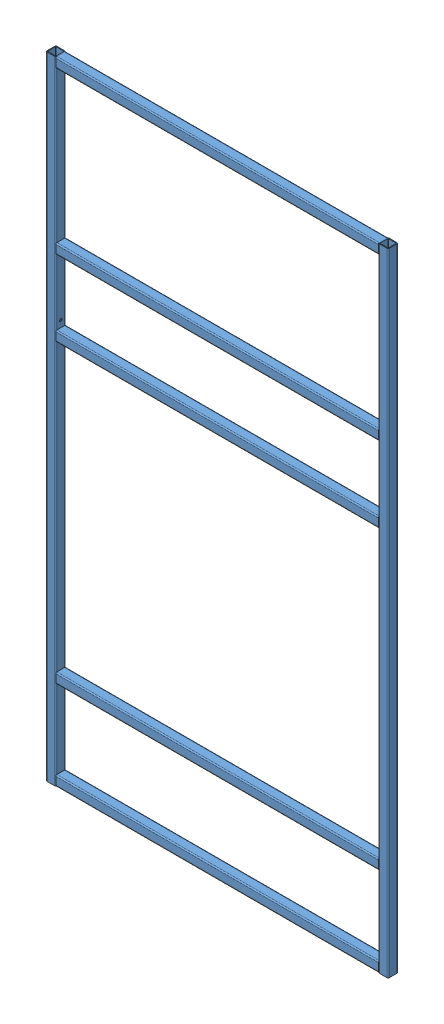
SolidWorks assembly 3D-printer R3 01.01.01 ASM side, configuration 15x15. Lengths in mm.
Overall size (520 960 15).
8 component instances, 2 part files, 21 mates.
Components (placement in the parent):
- dummy-1: dummy [По умолчанию] at origin (suppressed, hidden)
- 3D-printer R3 01.00.01 frame pipe-1: 3D-printer R3 01.00.01 frame pipe [01.00.01] at (252.5 0 7.5) x (1 0 0) z (0 1 0) size (15 15 960)
- 3D-printer R3 01.00.01 frame pipe-2: 3D-printer R3 01.00.01 frame pipe [01.00.01] at (-252.5 0 7.5) x (0 0 1) z (0 1 0) size (15 15 960)
- 3D-printer R3 01.00.01 frame pipe-3: 3D-printer R3 01.00.01 frame pipe [01.00.03] at (0 7.5 7.5) x (0 0 1) z (-1 0 0) size (15 15 490)
- 3D-printer R3 01.00.01 frame pipe-4: 3D-printer R3 01.00.01 frame pipe [01.00.03] at (0 142.5 7.5) x (0 0 -1) z (1 0 0) size (15 15 490)
- 3D-printer R3 01.00.01 frame pipe-5: 3D-printer R3 01.00.01 frame pipe [01.00.03] at (0 592.5 7.5) x (0 0 1) z (-1 0 0) size (15 15 490)
- 3D-printer R3 01.00.01 frame pipe-6: 3D-printer R3 01.00.01 frame pipe [01.00.03] at (0 707.5 7.5) x (0 0 -1) z (1 0 0) size (15 15 490)
- 3D-printer R3 01.00.01 frame pipe-7: 3D-printer R3 01.00.01 frame pipe [01.00.03] at (0 952.5 7.5) x (0 0 -1) z (1 0 0) size (15 15 490)
Mates (geometry in assembly coordinates):
- Coincident3: coincident anti-aligned: plane of 3D-printer R3 01.00.01 frame pipe-3 through (0 7.5 7.5) normal (-1 0 0); plane of assembly through (0 0 0) normal (1 0 0)
- Coincident13: coincident anti-aligned: plane of 3D-printer R3 01.00.01 frame pipe-3 through (245 7.5 7.5) normal (1 0 0); plane of 3D-printer R3 01.00.01 frame pipe-1 through (245 960 1.7) normal (-1 0 0)
- Coincident15: coincident aligned: plane of 3D-printer R3 01.00.01 frame pipe-1 through (252.5 0 7.5) normal (0 1 0); plane of 3D-printer R3 01.00.01 frame pipe-2 through (-252.5 0 7.5) normal (0 1 0)
- Coincident16: coincident anti-aligned: plane of 3D-printer R3 01.00.01 frame pipe-3 through (-245 7.5 7.5) normal (-1 0 0); plane of 3D-printer R3 01.00.01 frame pipe-2 through (-245 960 1.7) normal (1 0 0)
- Coincident17: coincident aligned: plane of 3D-printer R3 01.00.01 frame pipe-3 through (-245 13.3 15) normal (0 0 1); plane of 3D-printer R3 01.00.01 frame pipe-2 through (-245 960 1.7) normal (1 0 0)
- Coincident28: coincident aligned: plane of 3D-printer R3 01.00.01 frame pipe-4 through (245 150 13.3) normal (0 1 0); plane of assembly through (0 150 0) normal (0 1 0)
- Coincident29: coincident aligned: plane of 3D-printer R3 01.00.01 frame pipe-4 through (0 142.5 7.5) normal (1 0 0); plane of assembly through (0 0 0) normal (1 0 0)
- Coincident33: coincident aligned: plane of 3D-printer R3 01.00.01 frame pipe-6 through (245 715 13.3) normal (0 1 0); plane of assembly
- Coincident34: coincident aligned: plane of 3D-printer R3 01.00.01 frame pipe-6 through (0 707.5 7.5) normal (1 0 0); plane of assembly through (0 0 0) normal (1 0 0)
- Coincident36: coincident aligned: plane of 3D-printer R3 01.00.01 frame pipe-7 through (0 952.5 7.5) normal (1 0 0); plane of assembly through (0 0 0) normal (1 0 0)
- Coincident38: coincident aligned: plane of assembly through (0 0 0) normal (0 1 0); plane of 3D-printer R3 01.00.01 frame pipe-1 through (252.5 0 7.5) normal (0 1 0)
- Distance2: distance = 100 mm anti-aligned: plane of 3D-printer R3 01.00.01 frame pipe-6 through (245 700 13.3) normal (0 -1 0); plane of 3D-printer R3 01.00.01 frame pipe-5 through (-245 600 1.7) normal (0 1 0)
- Coincident41: coincident anti-aligned: plane of 3D-printer R3 01.00.01 frame pipe-1 through (245 960 1.7) normal (-1 0 0); plane of 3D-printer R3 01.00.01 frame pipe-5 through (245 592.5 7.5) normal (1 0 0)
- Coincident46: coincident anti-aligned: plane of 3D-printer R3 01.00.01 frame pipe-5 through (-245 585 1.7) normal (0 -1 0); plane of assembly through (0 585 0) normal (0 1 0)
- Coincident47: coincident aligned: plane of 3D-printer R3 01.00.01 frame pipe-3 through (-245 13.3 0) normal (0 0 -1); plane of 3D-printer R3 01.00.01 frame pipe-4 through (245 148.3 0) normal (0 0 -1)
- Coincident48: coincident aligned: plane of 3D-printer R3 01.00.01 frame pipe-3 through (-245 13.3 0) normal (0 0 -1); plane of 3D-printer R3 01.00.01 frame pipe-6 through (245 713.3 0) normal (0 0 -1)
- Coincident49: coincident aligned: plane of 3D-printer R3 01.00.01 frame pipe-3 through (-245 13.3 0) normal (0 0 -1); plane of 3D-printer R3 01.00.01 frame pipe-7 through (245 958.3 0) normal (0 0 -1)
- Coincident50: coincident aligned: plane of 3D-printer R3 01.00.01 frame pipe-3 through (-245 13.3 0) normal (0 0 -1); plane of 3D-printer R3 01.00.01 frame pipe-5 through (-245 598.3 0) normal (0 0 -1)
- Coincident51: coincident aligned: plane of 3D-printer R3 01.00.01 frame pipe-1 through (246.7 960 0) normal (0 0 -1); plane of assembly through (0 0 0) normal (0 0 -1)
- Coincident52: coincident aligned: plane of 3D-printer R3 01.00.01 frame pipe-3 through (-245 13.3 0) normal (0 0 -1); plane of assembly through (0 0 0) normal (0 0 -1)
- Coincident53: coincident aligned: plane of 3D-printer R3 01.00.01 frame pipe-2 through (-246.7 960 0) normal (0 0 -1); plane of assembly through (0 0 0) normal (0 0 -1)
